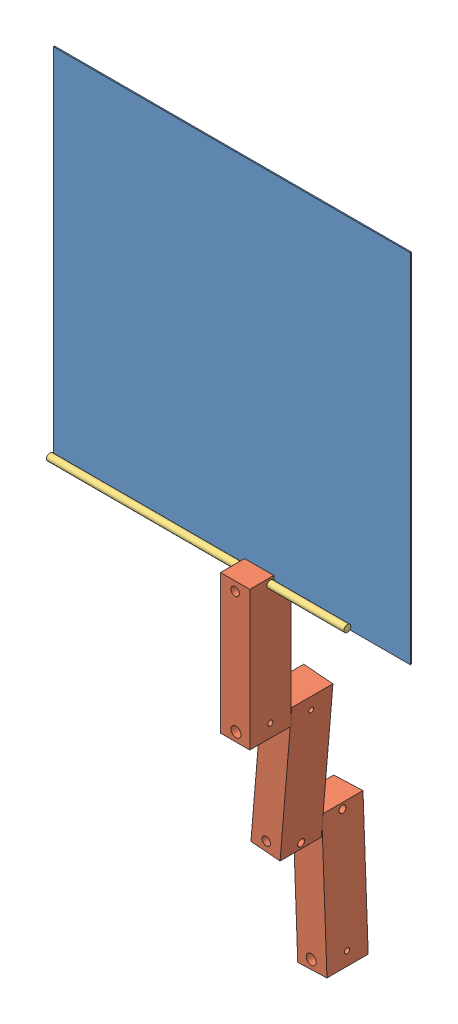
SolidWorks assembly 草图装配, configuration 默认. Lengths in mm.
Overall size (300 613.07 103.98).
5 component instances, 3 part files, 10 mates.
Components (placement in the parent):
- 工作体积-1: 工作体积 [默认] at origin size (300 300 1)
- 关节草图-1: 关节草图 [默认] at (185.2916 7.6781 -13.4301) x (0 0 1) z (0 -1 0) size (34.66 24.57 117)
- 关节草图-2: 关节草图 [默认] at (176.0914 -212.0616 -13.4301) x (0 0 -1) z (0.083591 0.9965 0) size (34.66 24.57 117)
- 固定座草图-1: 固定座草图 [默认] at (250 2.9 3.9) x (0 -0.258015 -0.966141) z (-1 0 0) size (5.8 5.8 250)
- 关节草图-3: 关节草图 [默认] at (151.9268 -196.1568 -48.0903) x (0 0 -1) z (0.037499 -0.999297 0) size (34.66 24.57 117)
Mates (geometry in assembly coordinates):
- 同心3: concentric anti-aligned: cylinder of 关节草图-1 through (173.6584 -101.8973 103.5699) axis (0 0 -1) radius 4.2421; cylinder of 关节草图-2 through (173.6584 -101.8973 -130.4301) axis (0 0 1) radius 4.2421
- 重合2: coincident anti-aligned: plane of 关节草图-1 through (185.2916 -109.3219 -13.4301) normal (0 0 -1); plane of 关节草图-2 through (185.8715 -95.4711 -13.4301) normal (0 0 1)
- 相切1: tangent aligned: plane of 工作体积-1 through (0 0 1) normal (0 -1 0); cylinder of 固定座草图-1 through (0 2.9 3.9) axis (1 0 0) radius 2.9
- 相切2: tangent anti-aligned: plane of 工作体积-1 through (0 0 1) normal (0 0 1); cylinder of 固定座草图-1 through (0 2.9 3.9) axis (1 0 0) radius 2.9
- 重合3: coincident: line of 工作体积-1 through (300 0 300) axis (0 0 -1); plane of 固定座草图-1 through (0 2.9 3.9) normal (-1 0 0)
- 同心4: concentric anti-aligned: cylinder of 关节草图-1 through (277.7212 2.9 3.9) axis (-1 0 0) radius 2.9365; cylinder of 固定座草图-1 through (0 2.9 3.9) axis (1 0 0) radius 2.9
- 同心5: concentric aligned: cylinder of 关节草图-2 through (164.4916 -203.3761 1.9097) axis (0 0 -1) radius 3.5327; cylinder of 关节草图-3 through (164.4916 -203.3761 -32.7505) axis (0 0 -1) radius 3.5327
- 重合5: coincident anti-aligned: plane of 关节草图-2 through (185.8715 -95.4711 -48.0903) normal (0 0 -1); plane of 关节草图-3 through (156.3142 -313.0745 -48.0903) normal (0 0 1)
- 距离2: distance = 64.7084 mm aligned: plane of 关节草图-1 through (185.2916 -109.3219 -13.4301) normal (1 0 0); plane of 固定座草图-1 through (250 2.9 3.9) normal (1 0 0)
- 垂直2: perpendicular: plane of 工作体积-1 through (0 0 1) normal (0 0 1); plane of 关节草图-1 through (185.2916 7.6781 -13.4301) normal (0 1 0)
